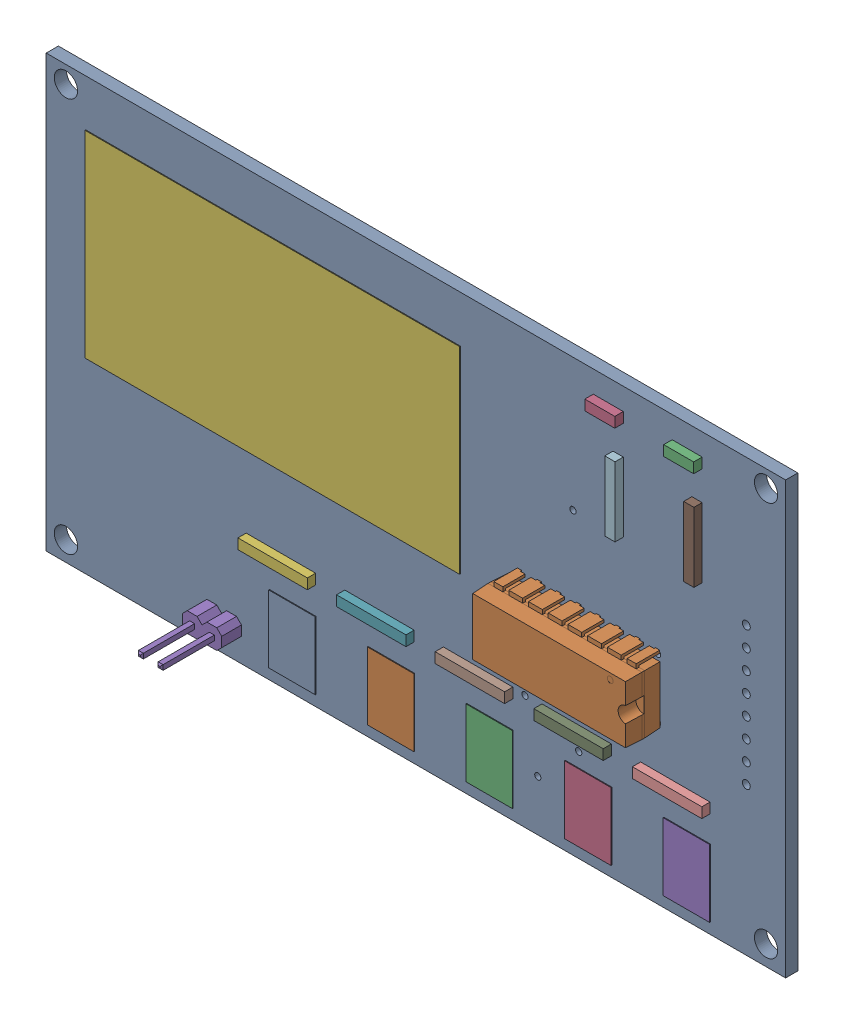
SolidWorks assembly PCB Component, configuration Default. Lengths in mm.
Overall size (95.23 55.55 12.97).
18 component instances, 7 part files, 0 mates.
Components (placement in the parent):
- Board-1: Board [Default] at origin size (95.23 55.55 1.57)
- 4532N-1: 4532N [Default] at (74.93 115.57 1.57) x (-1 0 0) z (0 0 1) size (19.81 8.66 8.71)
- LED3MM-1: LED3MM [Default] at (87.63 143.51 1.57) size (3.86 1.32 1.09)
- LED3MM-2: LED3MM [Default] at (77.47 143.51 1.57) size (3.86 1.32 1.09)
- 1X02-1: 1X02 [Default] at (27.686 95.123 1.57) size (5.08 2.54 12.64)
- 510-1: 510 [Default] at (35.306 105.664 1.57) x (-1 0 0) z (0 0 1) size (8.94 1.32 1.06)
- 510-2: 510 [Default] at (48.006 105.664 1.57) x (-1 0 0) z (0 0 1) size (8.94 1.32 1.06)
- 510-3: 510 [Default] at (60.706 105.664 1.57) x (-1 0 0) z (0 0 1) size (8.94 1.32 1.06)
- 510-4: 510 [Default] at (73.406 105.664 1.57) x (-1 0 0) z (0 0 1) size (8.94 1.32 1.06)
- 510-5: 510 [Default] at (86.106 105.537 1.57) x (-1 0 0) z (0 0 1) size (8.94 1.32 1.06)
- 510-6: 510 [Default] at (88.9 134.62 1.57) x (0 -1 0) z (0 0 1) size (8.94 1.32 1.06)
- 510-7: 510 [Default] at (78.74 134.62 1.57) x (0 -1 0) z (0 0 1) size (8.94 1.32 1.06)
- FSM8JH-1: FSM8JH [Default] at (36.83 97.79 1.57) x (0 1 0) z (0 0 1) size (8.7 6 0.1)
- FSM8JH-2: FSM8JH [Default] at (49.53 97.79 1.57) x (0 1 0) z (0 0 1) size (8.7 6 0.1)
- FSM8JH-3: FSM8JH [Default] at (62.23 97.79 1.57) x (0 1 0) z (0 0 1) size (8.7 6 0.1)
- FSM8JH-4: FSM8JH [Default] at (74.93 97.79 1.57) x (0 1 0) z (0 0 1) size (8.7 6 0.1)
- FSM8JH-5: FSM8JH [Default] at (87.63 97.79 1.57) x (0 1 0) z (0 0 1) size (8.7 6 0.1)
- ESP12E_DEVKIT-1: ESP12E_DEVKIT [Default] at (34.29 128.27 1.57) x (0 1 0) z (0 0 1) size (25.4 48.26 0.1)
